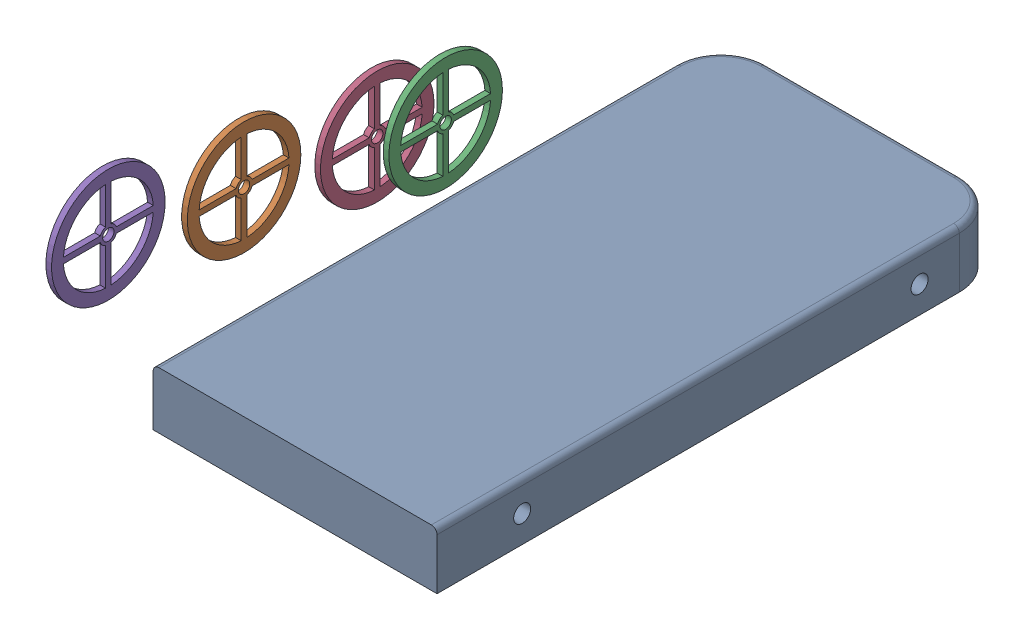
SolidWorks assembly tankbot, configuration Default. Lengths in mm.
Overall size (709.49 285.28 1000).
5 component instances, 2 part files, 0 mates.
Components (placement in the parent):
- base-1: base [Default] at (594.8026 1111.1598 1138.2968) size (500 100 1000)
- wheel-1: wheel [Default] at (480.0016 1296.4435 1873.3772) size (10 200 200)
- wheel-2: wheel [Default] at (524.6094 1261.7961 1562.9115) size (10 200 200)
- wheel-3: wheel [Default] at (510.7702 1287.3739 1669.5935) size (10 200 200)
- wheel-5: wheel [Default] at (385.3157 1248.9281 2017.788) size (10 200 200)
